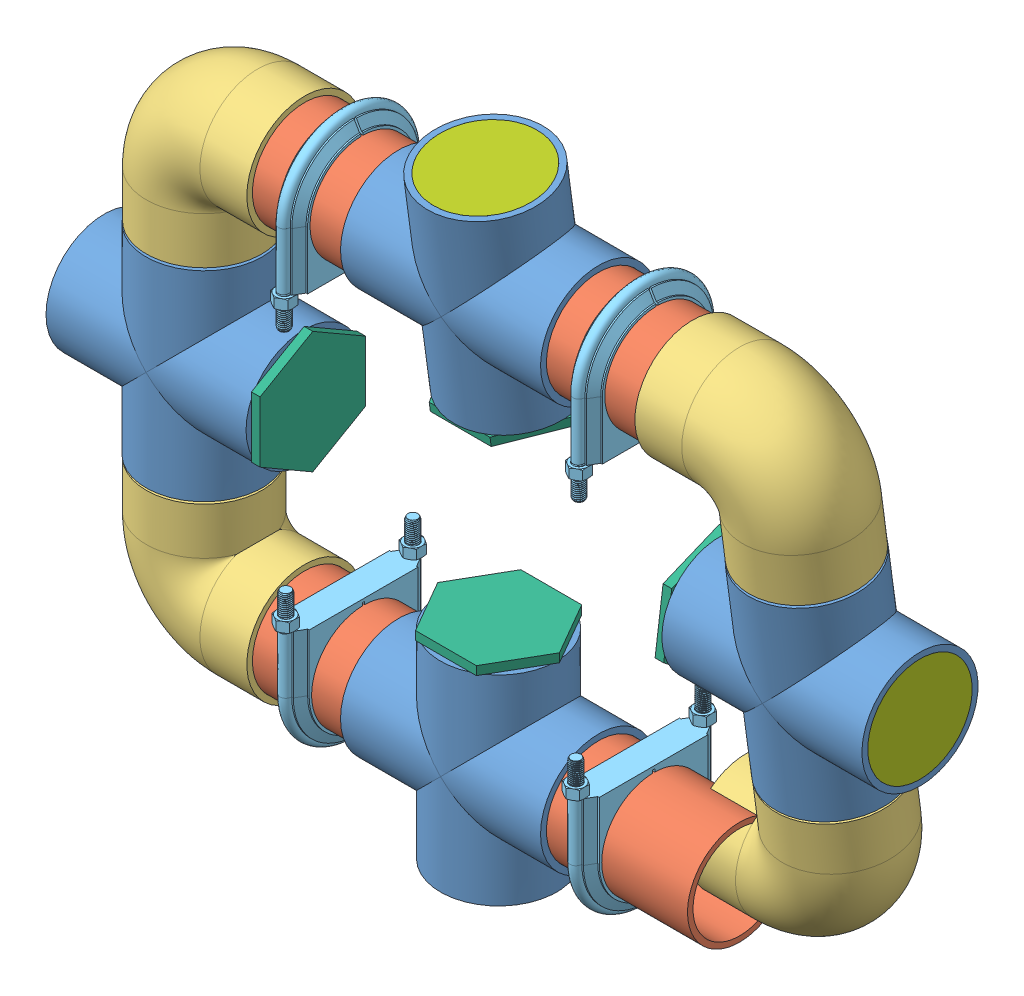
SolidWorks assembly PVC_frame, configuration Default. Lengths in mm.
Overall size (867.68 673.58 211.32).
28 component instances, 7 part files, 59 mates.
Components (placement in the parent):
- PVC_cross_fitting-1: PVC_cross_fitting [4880K249] at (-2200.7572 1205.9983 1212.5619) size (219.96 219.96 127.76)
- PVC_pipe-1: PVC_pipe [48925K98] at (-2038.7002 1205.9983 1212.5619) x (0 0 1) z (-1 0 0) size (114.3 114.3 205.75)
- PVC_pipe-2: PVC_pipe [48925K98] at (-2362.8142 1205.9983 1212.5619) x (0 0 -1) z (1 0 0) size (114.3 114.3 205.75)
- PVC_elbow-1: PVC_elbow [4880K28] at (-2524.6172 1205.9983 1212.5619) x (0 -1 0) z (0 0 1) size (173.99 173.99 127)
- PVC_pipe_2-1: PVC_pipe_2 [48925K98] at (-2524.6172 1317.4013 1212.5619) x (1 0 0) z (0 1 0) size (114.3 114.3 104.95)
- PVC_cross_fitting-2: PVC_cross_fitting [4880K249] at (-2524.6172 1429.0583 1212.5619) size (219.96 219.96 127.76)
- PVC_pipe_2-2: PVC_pipe_2 [48925K98] at (-2524.6172 1540.7153 1212.5619) x (1 0 0) z (0 1 0) size (114.3 114.3 104.95)
- PVC_elbow-2: PVC_elbow [4880K28] at (-2524.6172 1652.1183 1212.5619) x (0 1 0) z (0 0 -1) size (173.99 173.99 127)
- PVC_pipe-3: PVC_pipe [48925K98] at (-2362.8142 1652.1183 1212.5619) x (0 0 -1) z (1 0 0) size (114.3 114.3 205.75)
- PVC_cross_fitting-3: PVC_cross_fitting [4880K249] at (-2200.7572 1652.1183 1212.5619) x (1 0 0) z (0 -0.132508 0.991182) size (219.96 219.96 127.76)
- PVC_pipe-4: PVC_pipe [48925K98] at (-2038.7002 1652.1183 1212.5619) x (0 0 -1) z (1 0 0) size (114.3 114.3 205.75)
- PVC_elbow-3: PVC_elbow [4880K28] at (-1876.8972 1652.1183 1212.5619) x (1 0 0) z (0 0.132508 -0.991182) size (173.99 173.99 127)
- PVC_pipe_2-3: PVC_pipe_2 [48925K98] at (-1876.8972 1541.6977 1197.8001) x (1 0 0) z (0 -0.991182 -0.132508) size (114.3 114.3 104.95)
- PVC_cross_fitting-4: PVC_cross_fitting [4880K249] at (-1876.8972 1431.0253 1183.0046) x (1 0 0) z (0 -0.132508 0.991182) size (219.96 219.96 127.76)
- PVC_pipe_2-4: PVC_pipe_2 [48925K98] at (-1876.8972 1320.3529 1168.2092) x (1 0 0) z (0 -0.991182 -0.132508) size (114.3 114.3 104.95)
- PVC_elbow-4: PVC_elbow [4880K28] at (-1876.8972 1209.9322 1153.4474) x (1 0 0) z (0 -0.132508 0.991182) size (173.99 173.99 127)
- U_bolt_clamp-1: U_bolt_clamp [3176T41] at (-2366.6792 1553.0583 1212.5619) x (0 0 -1) z (1 0 0) size (161.7 175.58 31.5)
- U_bolt_clamp-2: U_bolt_clamp [3176T41] at (-2042.5362 1553.0583 1212.5619) x (0 0 -1) z (1 0 0) size (161.7 175.58 31.5)
- U_bolt_clamp-3: U_bolt_clamp [3176T41] at (-2045.929 1305.0583 1212.5619) x (0 0 -1) z (-1 0 0) size (161.7 175.58 31.5)
- U_bolt_clamp-4: U_bolt_clamp [3176T41] at (-2364.9292 1305.0583 1212.5619) x (0 0 1) z (1 0 0) size (161.7 175.58 31.5)
- PVC_end_cap-1: PVC_end_cap [4880K851] at (-2200.7572 1563.5617 1200.723) x (0 -0.991182 -0.132508) z (0 -0.132508 0.991182) size (60.32 133.82 115.89)
- PVC_end_cap-2: PVC_end_cap [4880K851] at (-1966.2417 1431.0253 1183.0046) x (-1 0 0) z (0 0.924225 0.381849) size (60.32 133.82 115.89)
- PVC_end_cap-3: PVC_end_cap [4880K851] at (-2435.2727 1429.0583 1212.5619) size (60.32 133.82 115.89)
- PVC_end_cap-4: PVC_end_cap [4880K851] at (-2200.7572 1295.3428 1212.5619) x (0 1 0) z (0 0 1) size (60.32 133.82 115.89)
- Camera_lense_protector-1: Camera_lense_protector [Default] at (-2200.7572 1761.1305 1227.1354) x (1 0 0) z (0 0.991182 0.132508) size (114.76 114.76 10)
- Camera_lense_protector-2: Camera_lense_protector [Default] at (-2624.5992 1429.0583 1212.5619) x (0 0 -1) z (1 0 0) size (114.76 114.76 10)
- Camera_lense_protector-3: Camera_lense_protector [Default] at (-2200.7572 1106.0163 1212.5619) x (1 0 0) z (0 1 0) size (114.76 114.76 10)
- Camera_lense_protector-4: Camera_lense_protector [Default] at (-1776.9152 1431.0253 1183.0046) x (0 0 1) z (-1 0 0) size (114.76 114.76 10)
Mates (geometry in assembly coordinates):
- Concentric5: concentric aligned: circle of PVC_cross_fitting-1; circle of PVC_pipe-1
- Coincident3: coincident anti-aligned: plane of PVC_cross_fitting-1 through (-2141.5752 1205.9983 1212.5619) normal (1 0 0); plane of PVC_pipe-1 through (-2141.5752 1205.9983 1212.5619) normal (-1 0 0)
- Concentric9: concentric anti-aligned: circle of PVC_cross_fitting-1; circle of PVC_pipe-2
- Coincident4: coincident anti-aligned: plane of PVC_cross_fitting-1 through (-2259.9392 1205.9983 1212.5619) normal (-1 0 0); plane of PVC_pipe-2 through (-2259.9392 1205.9983 1212.5619) normal (1 0 0)
- Concentric10: concentric anti-aligned: circle of PVC_pipe-2; circle of PVC_elbow-1
- Coincident5: coincident anti-aligned: plane of PVC_pipe-2 through (-2465.6892 1205.9983 1212.5619) normal (-1 0 0); plane of PVC_elbow-1 through (-2465.6892 1205.9983 1212.5619) normal (1 0 0)
- Concentric11: concentric aligned: circle of PVC_elbow-1; circle of PVC_pipe_2-1
- Coincident6: coincident anti-aligned: plane of PVC_elbow-1 through (-2524.6172 1264.9263 1212.5619) normal (0 1 0); plane of PVC_pipe_2-1 through (-2524.6172 1264.9263 1212.5619) normal (0 -1 0)
- Concentric12: concentric anti-aligned: circle of PVC_pipe_2-1; circle of PVC_cross_fitting-2
- Coincident7: coincident anti-aligned: plane of PVC_pipe_2-1 through (-2524.6172 1369.8763 1212.5619) normal (0 1 0); plane of PVC_cross_fitting-2 through (-2524.6172 1369.8763 1212.5619) normal (0 -1 0)
- Concentric13: concentric anti-aligned: circle of PVC_cross_fitting-2; circle of PVC_pipe_2-2
- Coincident8: coincident anti-aligned: plane of PVC_cross_fitting-2 through (-2524.6172 1488.2403 1212.5619) normal (0 1 0); plane of PVC_pipe_2-2 through (-2524.6172 1488.2403 1212.5619) normal (0 -1 0)
- Angle1: planar angle = 0 rad aligned: plane of PVC_elbow-2 through (-2414.1272 1715.6183 1212.5619) normal (1 0 0); plane of PVC_cross_fitting-2 through (-2414.6352 1365.1773 1212.5619) normal (1 0 0)
- Concentric16: concentric anti-aligned: circle of PVC_pipe_2-2; circle of PVC_elbow-2
- Coincident11: coincident anti-aligned: plane of PVC_pipe_2-2 through (-2524.6172 1593.1903 1212.5619) normal (0 1 0); plane of PVC_elbow-2 through (-2524.6172 1593.1903 1212.5619) normal (0 -1 0)
- Concentric17: concentric anti-aligned: circle of PVC_elbow-2; circle of PVC_pipe-3
- Coincident12: coincident anti-aligned: plane of PVC_elbow-2 through (-2465.6892 1652.1183 1212.5619) normal (1 0 0); plane of PVC_pipe-3 through (-2465.6892 1652.1183 1212.5619) normal (-1 0 0)
- Concentric18: concentric anti-aligned: circle of PVC_pipe-3; circle of PVC_cross_fitting-3
- Coincident13: coincident anti-aligned: plane of PVC_pipe-3 through (-2259.9392 1652.1183 1212.5619) normal (1 0 0); plane of PVC_cross_fitting-3 through (-2259.9392 1652.1183 1212.5619) normal (-1 0 0)
- Concentric19: concentric anti-aligned: circle of PVC_cross_fitting-3; circle of PVC_pipe-4
- Coincident14: coincident anti-aligned: plane of PVC_cross_fitting-3 through (-2141.5752 1652.1183 1212.5619) normal (1 0 0); plane of PVC_pipe-4 through (-2141.5752 1652.1183 1212.5619) normal (-1 0 0)
- Concentric20: concentric anti-aligned: circle of PVC_pipe-4; circle of PVC_elbow-3
- Parallel3: parallel anti-aligned: plane of PVC_cross_fitting-3 through (-2136.8762 1761.1305 1227.1354) normal (0 0.991182 0.132508); plane of PVC_elbow-3 through (-1813.3972 1542.6026 1197.9211) normal (0 -0.991182 -0.132508)
- Coincident15: coincident anti-aligned: circle of PVC_pipe-4; plane of PVC_elbow-3 through (-1935.8252 1652.1183 1212.5619) normal (-1 0 0)
- Concentric21: concentric anti-aligned: circle of PVC_elbow-3; circle of PVC_pipe_2-3
- Coincident16: coincident anti-aligned: plane of PVC_elbow-3 through (-1876.8972 1593.7099 1204.7534) normal (0 -0.991182 -0.132508); plane of PVC_pipe_2-3 through (-1876.8972 1593.7099 1204.7534) normal (0 0.991182 0.132508)
- Concentric22: concentric aligned: circle of PVC_pipe_2-3; circle of PVC_cross_fitting-4
- Coincident17: coincident anti-aligned: plane of PVC_pipe_2-3 through (-1876.8972 1489.6854 1190.8467) normal (0 -0.991182 -0.132508); plane of PVC_cross_fitting-4 through (-1876.8972 1489.6854 1190.8467) normal (0 0.991182 0.132508)
- Concentric23: concentric aligned: circle of PVC_cross_fitting-4; circle of PVC_pipe_2-4
- Coincident18: coincident anti-aligned: plane of PVC_cross_fitting-4 through (-1876.8972 1372.3651 1175.1625) normal (0 -0.991182 -0.132508); plane of PVC_pipe_2-4 through (-1876.8972 1372.3651 1175.1625) normal (0 0.991182 0.132508)
- Concentric25: concentric aligned: circle of PVC_pipe_2-4; circle of PVC_elbow-4
- Coincident19: coincident anti-aligned: circle of PVC_pipe_2-4; plane of PVC_elbow-4 through (-1876.8972 1268.3406 1161.2558) normal (0 0.991182 0.132508)
- Concentric26: concentric anti-aligned: cylinder of PVC_pipe-3 through (-2259.9392 1652.1183 1212.5619) axis (-1 0 0) radius 57.15; cylinder of U_bolt_clamp-1 through (-2382.4272 1652.1183 1212.5619) axis (1 0 0) radius 57.15
- Distance1: distance = 31.7 mm anti-aligned: plane of PVC_elbow-2 through (-2414.1272 1715.6183 1212.5619) normal (1 0 0); plane of U_bolt_clamp-1 through (-2382.4272 1652.1183 1215.7369) normal (-1 0 0)
- Concentric27: concentric anti-aligned: cylinder of PVC_pipe-4 through (-1935.8252 1652.1183 1212.5619) axis (-1 0 0) radius 57.15; cylinder of U_bolt_clamp-2 through (-2058.2842 1652.1183 1212.5619) axis (1 0 0) radius 57.15
- Distance3: distance = 39.4011 mm anti-aligned: plane of U_bolt_clamp-2 through (-2026.7882 1652.1183 1272.4442) normal (1 0 0); plane of PVC_elbow-3 through (-1987.3872 1715.0584 1220.9761) normal (-1 0 0)
- Concentric28: concentric anti-aligned: cylinder of PVC_pipe-1 through (-2141.5752 1205.9983 1212.5619) axis (1 0 0) radius 57.15; cylinder of U_bolt_clamp-3 through (-2030.181 1205.9983 1212.5619) axis (-1 0 0) radius 57.15
- Parallel4: parallel anti-aligned: line of U_bolt_clamp-3 through (-2030.181 1269.4983 1152.6796) axis (0 0 1); line of U_bolt_clamp-2 through (-2026.7882 1588.6183 1272.4442) axis (0 0 -1)
- Distance5: distance = 42.7938 mm anti-aligned: plane of U_bolt_clamp-3 through (-2030.181 1205.9983 1215.7369) normal (1 0 0); plane of PVC_elbow-4 through (-1987.3872 1146.9922 1145.0331) normal (-1 0 0)
- Concentric29: concentric anti-aligned: cylinder of PVC_pipe-2 through (-2259.9392 1205.9983 1212.5619) axis (-1 0 0) radius 57.15; cylinder of U_bolt_clamp-4 through (-2380.6772 1205.9983 1212.5619) axis (1 0 0) radius 57.15
- Parallel5: parallel anti-aligned: line of U_bolt_clamp-4 through (-2349.1812 1269.4983 1152.6796) axis (0 0 1); line of U_bolt_clamp-1 through (-2350.9312 1588.6183 1272.4442) axis (0 0 -1)
- Distance6: distance = 33.45 mm anti-aligned: plane of PVC_elbow-1 through (-2414.1272 1142.4983 1212.5619) normal (1 0 0); plane of U_bolt_clamp-4 through (-2380.6772 1205.9983 1209.3869) normal (-1 0 0)
- Coincident26: coincident anti-aligned: plane of PVC_cross_fitting-3 through (-2200.7572 1593.4582 1204.7198) normal (0 -0.991182 -0.132508); plane of PVC_end_cap-1 through (-2251.8874 1593.4582 1204.7198) normal (0 0.991182 0.132508)
- Concentric30: concentric anti-aligned: circle of PVC_cross_fitting-3; circle of PVC_end_cap-1
- Coincident27: coincident anti-aligned: plane of PVC_cross_fitting-4 through (-1936.0792 1431.0253 1183.0046) normal (-1 0 0); plane of PVC_end_cap-2 through (-1936.0792 1450.5493 1135.7488) normal (1 0 0)
- Concentric31: concentric anti-aligned: circle of PVC_cross_fitting-4; circle of PVC_end_cap-2
- Coincident28: coincident anti-aligned: plane of PVC_cross_fitting-1 through (-2200.7572 1265.1803 1212.5619) normal (0 1 0); plane of PVC_end_cap-4 through (-2149.627 1265.1803 1212.5619) normal (0 -1 0)
- Concentric32: concentric aligned: circle of PVC_cross_fitting-1; circle of PVC_end_cap-4
- Coincident29: coincident anti-aligned: plane of PVC_cross_fitting-2 through (-2465.4352 1429.0583 1212.5619) normal (1 0 0); plane of PVC_end_cap-3 through (-2465.4352 1377.9281 1212.5619) normal (-1 0 0)
- Concentric33: concentric aligned: circle of PVC_cross_fitting-2; circle of PVC_end_cap-3
- Concentric34: concentric anti-aligned: circle of PVC_cross_fitting-3; circle of Camera_lense_protector-1
- Concentric35: concentric anti-aligned: cone of PVC_cross_fitting-3 through (-2200.7572 1761.1305 1227.1354) axis (0 -0.991182 -0.132508); cylinder of Camera_lense_protector-1 through (-2200.7572 1751.2187 1225.8103) axis (0 0.991182 0.132508) radius 57.3785
- Coincident30: coincident aligned: plane of PVC_cross_fitting-3 through (-2136.8762 1761.1305 1227.1354) normal (0 0.991182 0.132508); plane of Camera_lense_protector-1 through (-2200.7572 1761.1305 1227.1354) normal (0 0.991182 0.132508)
- Concentric36: concentric aligned: cone of PVC_cross_fitting-4 through (-1766.9152 1431.0253 1183.0046) axis (-1 0 0); cylinder of Camera_lense_protector-4 through (-1766.9152 1431.0253 1183.0046) axis (-1 0 0) radius 57.3785
- Coincident32: coincident aligned: plane of PVC_cross_fitting-4 through (-1766.9152 1367.7076 1174.5399) normal (1 0 0); plane of Camera_lense_protector-4 through (-1766.9152 1431.0253 1183.0046) normal (1 0 0)
- Concentric38: concentric aligned: cone of PVC_cross_fitting-1 through (-2200.7572 1146.8163 1212.5619) axis (0 1 0); cylinder of Camera_lense_protector-3 through (-2200.7572 1096.0163 1212.5619) axis (0 1 0) radius 57.3785
- Coincident33: coincident aligned: plane of PVC_cross_fitting-1 through (-2136.8762 1096.0163 1212.5619) normal (0 -1 0); plane of Camera_lense_protector-3 through (-2200.7572 1096.0163 1212.5619) normal (0 -1 0)
- Concentric39: concentric aligned: cone of PVC_cross_fitting-2 through (-2583.7992 1429.0583 1212.5619) axis (1 0 0); cylinder of Camera_lense_protector-2 through (-2634.5992 1429.0583 1212.5619) axis (1 0 0) radius 57.3785
- Coincident34: coincident anti-aligned: plane of PVC_cross_fitting-2 through (-2634.5992 1365.1773 1212.5619) normal (-1 0 0); circle of Camera_lense_protector-2
